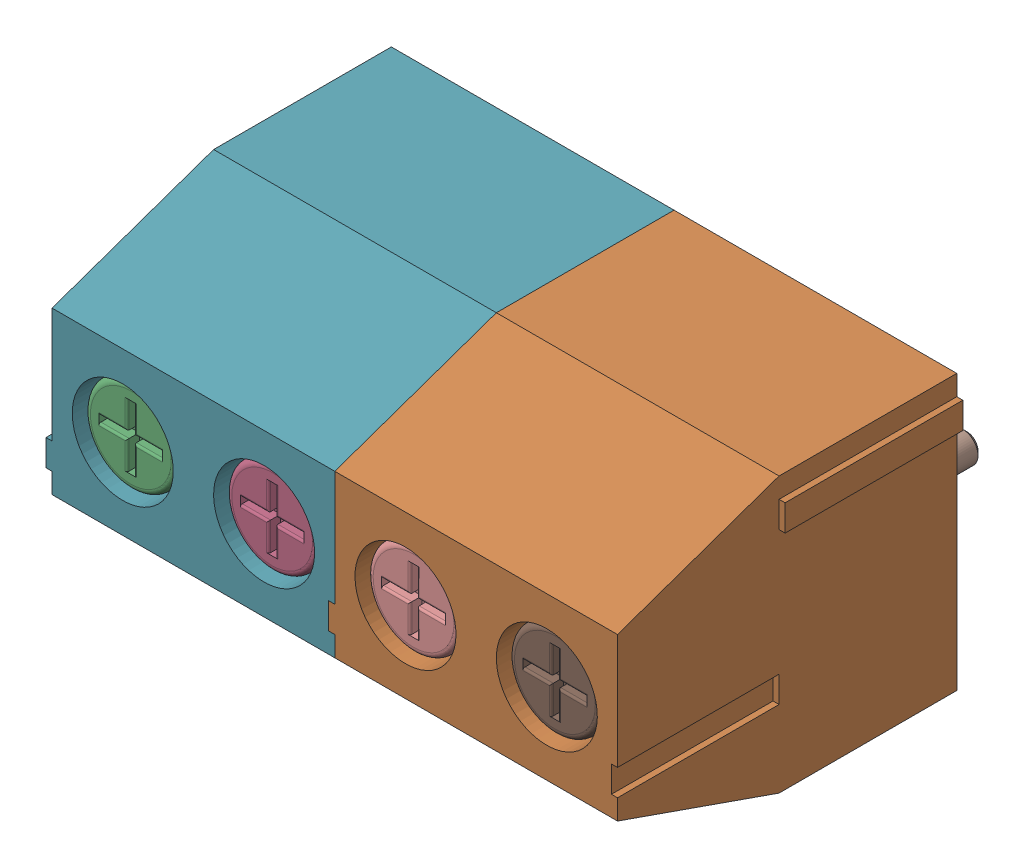
SolidWorks assembly TROYKA_AMPLIFIER_D__SCREWTERMINAL-3.5MM-4, configuration По умолчанию. Lengths in mm.
Overall size (14.3 6.8 10.4).
4 component instances, 1 part files, 0 mates.
Components (placement in the parent):
- TROYKA_AMPLIFIER_D__SCREWTERMINAL-3.5MM-2 v1 v1-1: TROYKA_AMPLIFIER_D__SCREWTERMINAL-3.5MM-2 v1 v1 [По умолчанию] at origin size (7.3 6.8 10.4)
  - TROYKA_AMPLIFIER_D_14420348.f3d -1: TROYKA_AMPLIFIER_D_14420348.f3d  [По умолчанию] at (1.75 0 0) x (1 0 0) z (0 -1 0) size (7.3 10.4 6.8)
- TROYKA_AMPLIFIER_D__SCREWTERMINAL-3.5MM-2 v1 v1-2: TROYKA_AMPLIFIER_D__SCREWTERMINAL-3.5MM-2 v1 v1 [По умолчанию] at (7 0 0) size (7.3 6.8 10.4)
  - TROYKA_AMPLIFIER_D_14420348.f3d -1: TROYKA_AMPLIFIER_D_14420348.f3d  [По умолчанию] at (1.75 0 0) x (1 0 0) z (0 -1 0) size (7.3 10.4 6.8)
